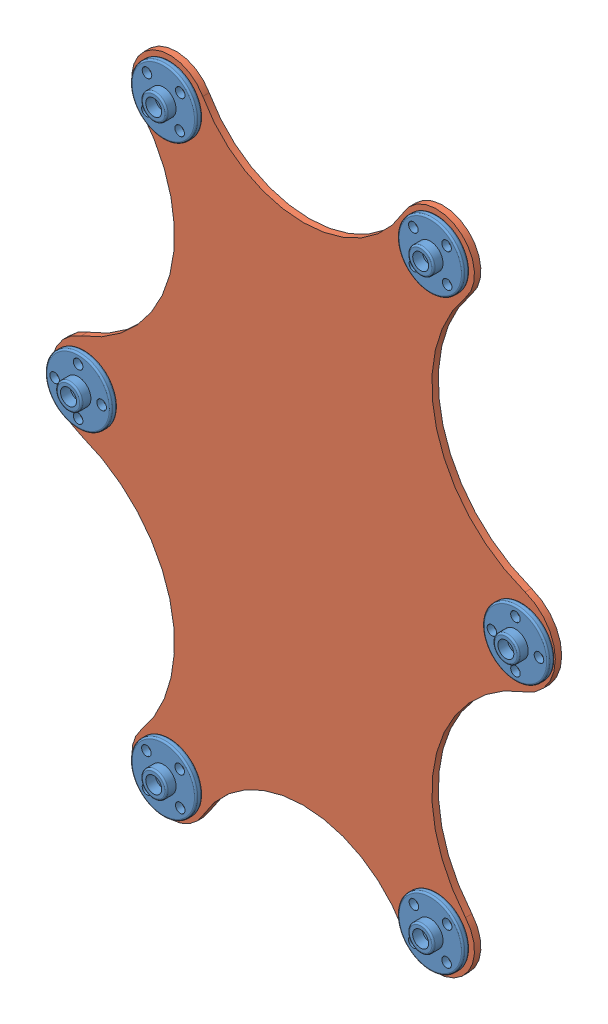
SolidWorks assembly 舵盘与躯体装配图, configuration 默认. Lengths in mm.
Overall size (157.64 212.39 7).
7 component instances, 2 part files, 18 mates.
Components (placement in the parent):
- 舵盘-1: 舵盘 [默认] at (-6.0794 0.1861 -2.5) size (20.5 20.5 5)
- 躯体 -1: 躯体  [默认] at (-147.2908 12.5584 -4.5) size (157.64 206.8 2)
- 舵盘-2: 舵盘 [默认] at (-116.163 -91.5165 -2.5) x (0.71934 -0.694658 0) z (0 0 1) size (20.5 20.5 5)
- 舵盘-3: 舵盘 [默认] at (-32.7147 91.8887 -2.5) x (0.71934 -0.694658 0) z (0 0 1) size (20.5 20.5 5)
- 舵盘-4: 舵盘 [默认] at (-32.7147 -91.5165 -2.5) x (-0.694658 0.71934 0) z (0 0 1) size (20.5 20.5 5)
- 舵盘-5: 舵盘 [默认] at (-116.163 91.8887 -2.5) x (0.71934 0.694658 0) z (0 0 1) size (20.5 20.5 5)
- 舵盘-7: 舵盘 [默认] at (-142.7982 0.1861 -2.5) size (20.5 20.5 5)
Mates (geometry in assembly coordinates):
- 重合1: coincident anti-aligned: plane of 舵盘-1 through (-6.0794 0.1861 -2.5) normal (0 0 -1); plane of 躯体 -1 through (-147.2908 12.5584 -2.5) normal (0 0 1)
- 重合2: coincident anti-aligned: plane of 躯体 -1 through (-147.2908 12.5584 -2.5) normal (0 0 1); plane of 舵盘-3 through (-32.7147 91.8887 -2.5) normal (0 0 -1)
- 重合4: coincident anti-aligned: plane of 躯体 -1 through (-147.2908 12.5584 -2.5) normal (0 0 1); plane of 舵盘-4 through (-32.7147 -91.5165 -2.5) normal (0 0 -1)
- 同心7: concentric aligned: circle of 躯体 -1; circle of 舵盘-5
- 重合5: coincident anti-aligned: plane of 躯体 -1 through (-147.2908 12.5584 -2.5) normal (0 0 1); circle of 舵盘-5
- 重合6: coincident anti-aligned: plane of 躯体 -1 through (-147.2908 12.5584 -2.5) normal (0 0 1); plane of 舵盘-7 through (-142.7982 0.1861 -2.5) normal (0 0 -1)
- 重合7: coincident anti-aligned: plane of 躯体 -1 through (-147.2908 12.5584 -2.5) normal (0 0 1); plane of 舵盘-2 through (-116.163 -91.5165 -2.5) normal (0 0 -1)
- 同心9: concentric aligned: circle of 躯体 -1; circle of 舵盘-7
- 同心10: concentric aligned: circle of 躯体 -1; circle of 舵盘-7
- 同心11: concentric anti-aligned: circle of 躯体 -1; circle of 舵盘-3
- 同心12: concentric anti-aligned: circle of 躯体 -1; circle of 舵盘-3
- 同心13: concentric aligned: circle of 舵盘-1; circle of 躯体 -1
- 同心14: concentric anti-aligned: circle of 舵盘-1; circle of 躯体 -1
- 同心15: concentric aligned: circle of 躯体 -1; circle of 舵盘-4
- 同心16: concentric aligned: circle of 躯体 -1; circle of 舵盘-4
- 同心17: concentric anti-aligned: circle of 躯体 -1; circle of 舵盘-2
- 同心18: concentric anti-aligned: circle of 躯体 -1; circle of 舵盘-2
- 同心19: concentric anti-aligned: cylinder of 躯体 -1 through (-116.163 91.8887 -2.5) axis (0 0 -1) radius 1.65; circle of 舵盘-5
